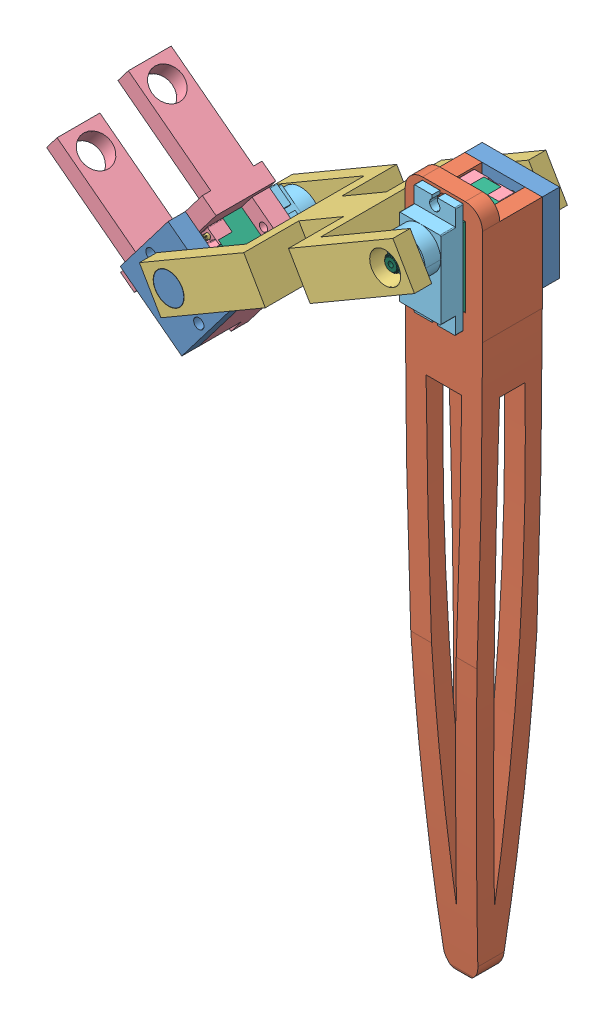
SolidWorks assembly Leg assamble, configuration Default. Lengths in mm.
Overall size (121.73 200 44.3).
47 component instances, 22 part files, 16 mates.
Components (placement in the parent):
- CoverLeg-1: CoverLeg [Default] at (5.4977 12.0108 18.4868) size (22.4 22.9 10)
- LowLeg-1: LowLeg [Default] at (5.4977 12.0108 35.7868) size (22.4 200 18.22)
- JoinLeg-1: JoinLeg [Default] at (-19.3858 2.7607 35.6368) x (0 0 -1) z (0.86401 0.503474 0) size (44.3 12.4 85)
- CoverLeg-3: CoverLeg [Default] at (-60.4098 -23.4685 52.7868) x (-0.795632 0.605781 0) z (0 0 -1) size (22.4 22.9 10)
- MG90S-1: MG90S [Default] at (-15.7901 -20.7716 66.5373) x (1 0 0) z (0 -1 0) size (13.58 32.57 32)
  - MG90S.STEP-1: MG90S.STEP [Default] at origin size (13.58 32.57 32)
    - Part1.STEP-1: Part1.STEP [Default] at (21.0878 -43.0505 -32.5824) x (0 0 -1) z (1 0 0) size (22.54 9.07 12)
    - Part2.STEP-1: Part2.STEP [Default] at (21.0878 -25.5505 -32.5824) x (0 0 -1) z (1 0 0) size (32 13 12)
    - Part3.STEP-1: Part3.STEP [Default] at (21.0878 -36.0505 -32.5824) x (0 0 -1) z (1 0 0) size (22.5 16 12)
    - spur gear_iso_ISO - Spur gear 0.25M 38T 20PA 1.5FW ---S38A75H50L1.5N.STEP-1: spur gear_iso_ISO - Spur gear 0.25M 38T 20PA 1.5FW ---S38A75H50L1.5N.STEP [Default] at (21.0878 -22.3005 -37.8324) x (0 -1 0) z (0.87496 0 0.484196) size (1.5 9.98 10)
    - spur gear_iso_ISO - Spur gear 0.3M 31T 20PA 2FW ---S31A75H50L1.25N.STEP-1: spur gear_iso_ISO - Spur gear 0.3M 31T 20PA 2FW ---S31A75H50L1.25N.STEP [Default] at (21.0878 -19.8005 -31.3324) x (0 -1 0) z (0.109568 0 -0.993979) size (2 9.88 9.89)
    - spur gear_iso_ISO - Spur gear 0.4M 23T 20PA 2.75FW ---S23A75H50L1.5N.STEP-1: spur gear_iso_ISO - Spur gear 0.4M 23T 20PA 2.75FW ---S23A75H50L1.5N.STEP [Default] at (21.0878 -19.8005 -37.8324) x (0 1 0) z (-0.993238 0 0.116099) size (2.75 9.97 9.99)
    - spur gear_iso_ISO - Spur gear 0.25M 31T 20PA 1.25FW ---S31A75H50L1.25N.STEP-1: spur gear_iso_ISO - Spur gear 0.25M 31T 20PA 1.25FW ---S31A75H50L1.25N.STEP [Default] at (21.0878 -25.0505 -31.3324) x (0 1 0) z (0.977188 0 0.212376) size (1.25 8.24 8.25)
    - spur gear_iso_ISO - Spur gear 0.25M 10T 20PA 2FW ---S10A75H50L1.25N.STEP-1: spur gear_iso_ISO - Spur gear 0.25M 10T 20PA 2FW ---S10A75H50L1.25N.STEP [Default] at (21.0878 -23.8005 -31.3324) x (0 1 0) z (0.977188 0 0.212376) size (2 2.87 3)
    - gear3.STEP-1: gear3.STEP [Default] at (21.0878 -22.3005 -37.8324) x (0.87496 0 0.484196) z (-0.484196 0 0.87496) size (3.98 2.5 3.92)
    - gear1.STEP-1: gear1.STEP [Default] at (21.0878 -19.8005 -31.3324) x (0.109568 0 -0.993979) z (0.993979 0 0.109568) size (3.96 2.5 3.87)
    - gear2.STEP-1: gear2.STEP [Default] at (21.0878 -26.3005 -26.3324) x (0.891105 0 -0.453797) z (0.453797 0 0.891105) size (2.5 2.5 2.5)
    - Part4.STEP-1: Part4.STEP [Default] at (21.0878 -17.0505 -37.8324) x (0.993238 0 -0.116099) z (0.116099 0 0.993238) size (4.5 6.5 4.5)
    - Motor_Body.STEP-1: Motor_Body.STEP [Default] at (21.0878 -26.5505 -26.3324) x (-1 0 0) z (0 0 1) size (10 14.25 8)
    - Motor_Body2.STEP-1: Motor_Body2.STEP [Default] at (21.0878 -39.0505 -26.3324) size (10 2 8)
    - cilinder2.STEP-1: cilinder2.STEP [Default] at (21.0878 -31.8005 -37.8324) x (0.116099 0 0.993238) z (-0.993238 0 0.116099) size (1.5 15 1.5)
    - cilinder1.STEP-1: cilinder1.STEP [Default] at (21.0878 -27.3005 -31.3324) x (0.109568 0 -0.993979) z (0.993979 0 0.109568) size (1.25 12 1.25)
    - Part5.STEP-1: Part5.STEP [Default] at (21.0878 -40.0505 -32.0824) x (0 0 -1) z (1 0 0) size (19.28 16 10.15)
    - Part6.STEP-1: Part6.STEP [Default] at (16.5878 -42.0505 -22.8324) size (1.5 21 1.5)
    - Part6.STEP-2: Part6.STEP [Default] at (25.5878 -40.5505 -42.3324) size (1.5 21 1.5)
- MG90S-2: MG90S [Default] at (-63.4075 -61.8864 4.9363) x (-0.795632 0.605781 0) z (-0.605781 -0.795632 0) size (13.58 32.57 32)
  - MG90S.STEP-1: MG90S.STEP [Default] at origin size (13.58 32.57 32)
    - Part1.STEP-1: Part1.STEP [Default] at (21.0878 -43.0505 -32.5824) x (0 0 -1) z (1 0 0) size (22.54 9.07 12)
    - Part2.STEP-1: Part2.STEP [Default] at (21.0878 -25.5505 -32.5824) x (0 0 -1) z (1 0 0) size (32 13 12)
    - Part3.STEP-1: Part3.STEP [Default] at (21.0878 -36.0505 -32.5824) x (0 0 -1) z (1 0 0) size (22.5 16 12)
    - spur gear_iso_ISO - Spur gear 0.25M 38T 20PA 1.5FW ---S38A75H50L1.5N.STEP-1: spur gear_iso_ISO - Spur gear 0.25M 38T 20PA 1.5FW ---S38A75H50L1.5N.STEP [Default] at (21.0878 -22.3005 -37.8324) x (0 -1 0) z (0.87496 0 0.484196) size (1.5 9.98 10)
    - spur gear_iso_ISO - Spur gear 0.3M 31T 20PA 2FW ---S31A75H50L1.25N.STEP-1: spur gear_iso_ISO - Spur gear 0.3M 31T 20PA 2FW ---S31A75H50L1.25N.STEP [Default] at (21.0878 -19.8005 -31.3324) x (0 -1 0) z (0.109568 0 -0.993979) size (2 9.88 9.89)
    - spur gear_iso_ISO - Spur gear 0.4M 23T 20PA 2.75FW ---S23A75H50L1.5N.STEP-1: spur gear_iso_ISO - Spur gear 0.4M 23T 20PA 2.75FW ---S23A75H50L1.5N.STEP [Default] at (21.0878 -19.8005 -37.8324) x (0 1 0) z (-0.993238 0 0.116099) size (2.75 9.97 9.99)
    - spur gear_iso_ISO - Spur gear 0.25M 31T 20PA 1.25FW ---S31A75H50L1.25N.STEP-1: spur gear_iso_ISO - Spur gear 0.25M 31T 20PA 1.25FW ---S31A75H50L1.25N.STEP [Default] at (21.0878 -25.0505 -31.3324) x (0 1 0) z (0.977188 0 0.212376) size (1.25 8.24 8.25)
    - spur gear_iso_ISO - Spur gear 0.25M 10T 20PA 2FW ---S10A75H50L1.25N.STEP-1: spur gear_iso_ISO - Spur gear 0.25M 10T 20PA 2FW ---S10A75H50L1.25N.STEP [Default] at (21.0878 -23.8005 -31.3324) x (0 1 0) z (0.977188 0 0.212376) size (2 2.87 3)
    - gear3.STEP-1: gear3.STEP [Default] at (21.0878 -22.3005 -37.8324) x (0.87496 0 0.484196) z (-0.484196 0 0.87496) size (3.98 2.5 3.92)
    - gear1.STEP-1: gear1.STEP [Default] at (21.0878 -19.8005 -31.3324) x (0.109568 0 -0.993979) z (0.993979 0 0.109568) size (3.96 2.5 3.87)
    - gear2.STEP-1: gear2.STEP [Default] at (21.0878 -26.3005 -26.3324) x (0.891105 0 -0.453797) z (0.453797 0 0.891105) size (2.5 2.5 2.5)
    - Part4.STEP-1: Part4.STEP [Default] at (21.0878 -17.0505 -37.8324) x (0.993238 0 -0.116099) z (0.116099 0 0.993238) size (4.5 6.5 4.5)
    - Motor_Body.STEP-1: Motor_Body.STEP [Default] at (21.0878 -26.5505 -26.3324) x (-1 0 0) z (0 0 1) size (10 14.25 8)
    - Motor_Body2.STEP-1: Motor_Body2.STEP [Default] at (21.0878 -39.0505 -26.3324) size (10 2 8)
    - cilinder2.STEP-1: cilinder2.STEP [Default] at (21.0878 -31.8005 -37.8324) x (0.116099 0 0.993238) z (-0.993238 0 0.116099) size (1.5 15 1.5)
    - cilinder1.STEP-1: cilinder1.STEP [Default] at (21.0878 -27.3005 -31.3324) x (0.109568 0 -0.993979) z (0.993979 0 0.109568) size (1.25 12 1.25)
    - Part5.STEP-1: Part5.STEP [Default] at (21.0878 -40.0505 -32.0824) x (0 0 -1) z (1 0 0) size (19.28 16 10.15)
    - Part6.STEP-1: Part6.STEP [Default] at (16.5878 -42.0505 -22.8324) size (1.5 21 1.5)
    - Part6.STEP-2: Part6.STEP [Default] at (25.5878 -40.5505 -42.3324) size (1.5 21 1.5)
- JointChassis-4: JointChassis [Default] at (-60.4098 -23.4685 30.4868) x (-0.605781 -0.795632 0) z (0 0 1) size (39.1 52.4 17.3)
Mates (geometry in assembly coordinates):
- Coincident3: coincident anti-aligned: line of CoverLeg-1 through (16.6977 0.5608 23.4868) axis (0 1 0); line of LowLeg-1 through (16.6977 23.4608 23.4868) axis (0 -1 0)
- Coincident4: coincident anti-aligned: line of CoverLeg-1 through (16.6977 23.4608 23.4868) axis (-1 0 0); line of LowLeg-1 through (11.6977 23.4608 23.4868) axis (1 0 0)
- Coincident5: coincident anti-aligned: plane of CoverLeg-1 through (5.4977 12.0108 18.4868) normal (0 0 -1); plane of JoinLeg-1 through (7.733 25.7392 18.4868) normal (0 0 1)
- Concentric1: concentric anti-aligned: cylinder of CoverLeg-1 through (5.4977 17.2608 13.4868) axis (0 0 1) radius 4.4; cylinder of JoinLeg-1 through (5.4977 17.2608 63.4868) axis (0 0 -1) radius 4.5
- Coincident23: coincident anti-aligned: plane of JoinLeg-1 through (-65.7079 -17.0561 52.7868) normal (0 0 -1); plane of CoverLeg-3 through (-60.4098 -23.4685 52.7868) normal (0 0 1)
- Concentric2: concentric anti-aligned: cylinder of JoinLeg-1 through (-57.2295 -19.2914 7.7868) axis (0 0 1) radius 4.5; cylinder of CoverLeg-3 through (-57.2295 -19.2914 57.7868) axis (0 0 -1) radius 4.4
- Coincident25: coincident anti-aligned: plane of CoverLeg-1 through (5.4977 12.0108 23.4868) normal (0 0 1); plane of MG90S-1/MG90S.STEP-1/Part1.STEP-1 through (5.2977 11.8108 23.4868) normal (0 0 -1)
- Coincident26: coincident anti-aligned: plane of LowLeg-1 through (-0.7023 0.5608 35.7868) normal (0 1 0); plane of MG90S-1/MG90S.STEP-1/Part2.STEP-1 through (11.2977 0.5608 47.4868) normal (0 -1 0)
- Coincident27: coincident anti-aligned: plane of LowLeg-1 through (-0.7023 23.4608 35.7868) normal (1 0 0); plane of MG90S-1/MG90S.STEP-1/Part3.STEP-1 through (-0.7023 23.0608 40.9868) normal (-1 0 0)
- Parallel2: parallel anti-aligned: plane of MG90S-2/MG90S.STEP-1/Part2.STEP-1 through (-60.4478 -23.1882 30.4868) normal (0 0 1); plane of JointChassis-4 through (-60.4098 -23.4685 30.4868) normal (0 0 -1)
- Coincident43: coincident anti-aligned: plane of MG90S-2/MG90S.STEP-1/Part3.STEP-1 through (-58.4065 -10.6027 30.4868) normal (-0.795632 0.605781 0); plane of JointChassis-4 through (-58.4065 -10.6027 30.4868) normal (0.795632 -0.605781 0)
- Coincident44: coincident aligned: plane of MG90S-2/MG90S.STEP-1/Part3.STEP-1 through (-58.4065 -10.6027 30.4868) normal (0.605781 0.795632 0); plane of JointChassis-4 through (-48.5407 -18.1144 47.7868) normal (0.605781 0.795632 0)
- Coincident52: coincident anti-aligned: plane of MG90S-2/MG90S.STEP-1/Part2.STEP-1 through (-60.4478 -23.1882 30.4868) normal (0 0 1); plane of JointChassis-4 through (-60.4098 -23.4685 30.4868) normal (0 0 -1)
- Coincident53: coincident anti-aligned: line of CoverLeg-3 through (-76.2571 -25.7937 47.7868) axis (0.605781 0.795632 0); line of JointChassis-4 through (-57.4779 -1.1292 47.7868) axis (-0.605781 -0.795632 0)
- Coincident54: coincident anti-aligned: plane of CoverLeg-3 through (-60.4098 -23.4685 47.7868) normal (0 0 -1); plane of JointChassis-4 through (-60.4098 -23.4685 47.7868) normal (0 0 1)
- Coincident55: coincident anti-aligned: line of CoverLeg-3 through (-62.3847 -7.5738 47.7868) axis (0.795632 -0.605781 0); line of JointChassis-4 through (-44.5626 -21.1433 47.7868) axis (-0.795632 0.605781 0)
